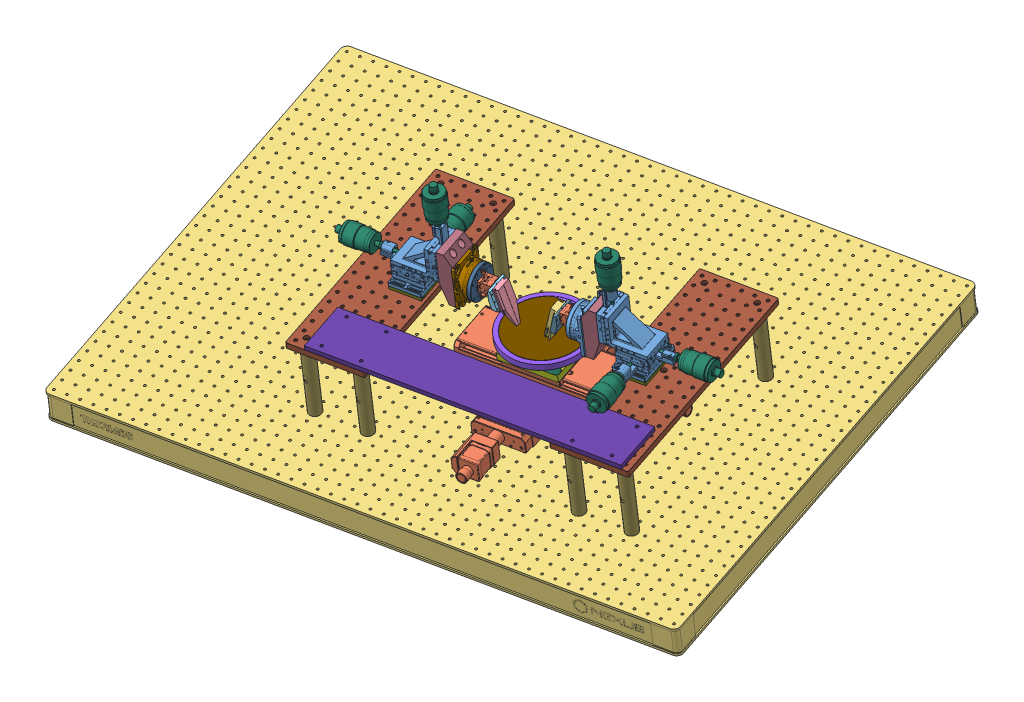
SolidWorks assembly Setup, configuration Default. Lengths in mm.
Overall size (1384.71 521 1150.45).
40 component instances, 21 part files, 108 mates.
Components (placement in the parent):
- 462-XYZ-M-2: 462-XYZ-M [Default] at (49.8158 -112.9792 618.0532) x (0.208851 -0.167911 0.963425) z (-0.977017 0.007153 0.213044) size (111.33 137.01 128.04)
- M-406.62S-4: M-406.62S [Default] at (251.5872 -279.1088 517.8324) x (0.208851 -0.167911 0.963425) z (0.042664 0.985776 0.162558) size (419.5 106.5 40)
- B3648F-Solidworks-1: B3648F-Solidworks [Default] at (-379.5647 -399.4119 1043.9168) x (0.977017 -0.007153 -0.213044) z (0.208851 -0.167911 0.963425) size (1219.2 60 914.4)
- M-406.62S-5: M-406.62S [Default] at (252.9966 -239.634 524.1473) x (0.977017 -0.007153 -0.213044) z (0.042664 0.985776 0.162558) size (419.5 106.5 40)
- HFV002-Solidworks-1: HFV002-Solidworks [Default] at (201.4749 -76.76 602.3122) x (0.208851 -0.167911 0.963425) z (-0.211661 0.954038 0.212159) size (32 13.8 82.5)
- fiber holder adaptor_v2-2: fiber holder adaptor_v2 [Default] at (208.543 -65.9697 592.0326) x (0.977017 -0.007153 -0.213044) z (0.208851 -0.167911 0.963425) size (16.3 42.46 45)
- RP03-Solidworks-1: RP03-Solidworks [Default] at (255.4491 -184.219 533.5338) x (0.977017 -0.007153 -0.213044) z (0.208851 -0.167911 0.963425) size (118.11 17.77 118.11)
- rotation stage adaptor-1: rotation stage adaptor [Default] at (255.3955 -185.4584 533.3295) x (0.977017 -0.007153 -0.213044) z (0.208851 -0.167911 0.963425) size (118.11 15 118.11)
- Wafer chuck-3: Wafer chuck [Default] at (256.7081 -155.1287 538.3309) x (0.208851 -0.167911 0.963425) z (-0.977017 0.007153 0.213044) size (170 13 170)
- PR01 + adaptor-1: PR01 + adaptor [Default] at (135.5181 -100.5643 655.1645) x (0.042664 0.985776 0.162558) z (-0.208851 0.167911 -0.963425) size (88.9 32.89 82.68)
  - PR01-Solidworks-1: PR01-Solidworks [Default] at (32.836 6.2197 50.44) size (88.9 25.27 82.68)
  - PR01A-Solidworks-1: PR01A-Solidworks [Default] at (20.0486 45.6101 48.8975) size (68.58 7.62 68.58)
- MB618-Solidworks-1: MB618-Solidworks [Default] at (11.6774 -131.5526 623.5055) x (-0.208851 0.167911 -0.963425) z (0.977017 -0.007153 -0.213044) size (457.2 12.7 152.4)
- RS6-Solidworks-1: RS6-Solidworks [Default] at (101.1502 -239.3366 794.9313) x (0.999084 -0.042649 -0.003583) z (-0.0034 -0.162562 0.986692) size (25.37 152.4 25.57)
- RS6-Solidworks-2: RS6-Solidworks [Default] at (1.8853 -238.6099 816.5765) x (0.999084 -0.042649 -0.003583) z (-0.0034 -0.162562 0.986692) size (25.37 152.4 25.57)
- RS6-Solidworks-3: RS6-Solidworks [Default] at (-82.9916 -170.3709 425.0407) x (0.999084 -0.042649 -0.003583) z (-0.0034 -0.162562 0.986692) size (25.37 152.4 25.57)
- RS6-Solidworks-4: RS6-Solidworks [Default] at (16.2733 -171.0976 403.3954) x (0.999084 -0.042649 -0.003583) z (-0.0034 -0.162562 0.986692) size (25.37 152.4 25.57)
- XYZ_to_rotation_adapter-1: XYZ_to_rotation_adapter [Default] at (143.7201 -49.9652 576.181) x (0.977017 -0.007153 -0.213044) z (0.208851 -0.167911 0.963425) size (30 110.9 63)
- RS6-Solidworks-5: RS6-Solidworks [Default] at (498.2097 -242.2436 708.3503) x (0.999084 -0.042649 -0.003583) z (-0.0034 -0.162562 0.986692) size (25.37 152.4 25.57)
- RS6-Solidworks-6: RS6-Solidworks [Default] at (597.4746 -242.9703 686.7051) x (0.999084 -0.042649 -0.003583) z (-0.0034 -0.162562 0.986692) size (25.37 152.4 25.57)
- RS6-Solidworks-7: RS6-Solidworks [Default] at (413.3328 -174.0045 316.8145) x (0.999084 -0.042649 -0.003583) z (-0.0034 -0.162562 0.986692) size (25.37 152.4 25.57)
- RS6-Solidworks-8: RS6-Solidworks [Default] at (512.5977 -174.7313 295.1693) x (0.999084 -0.042649 -0.003583) z (-0.0034 -0.162562 0.986692) size (25.37 152.4 25.57)
- MB618-Solidworks-2: MB618-Solidworks [Default] at (508.0018 -135.1863 515.2794) x (0.208851 -0.167911 0.963425) z (-0.977017 0.007153 0.213044) size (457.2 12.7 152.4)
- 462-XYZ-M-3: 462-XYZ-M [Default] at (471.489 -116.2016 526.9252) x (-0.208851 0.167911 -0.963425) z (0.977017 -0.007153 -0.213044) size (111.33 137.01 128.04)
- XYZ_to_rotation_adapter-2: XYZ_to_rotation_adapter [Default] at (382.646 -62.2683 588.0824) x (-0.977017 0.007153 0.213044) z (-0.208851 0.167911 -0.963425) size (30 110.9 63)
- fiber holder adaptor-3: fiber holder adaptor [Default] at (316.9328 -66.8359 568.8384) x (-0.977017 0.007153 0.213044) z (-0.208851 0.167911 -0.963425) size (16.3 42.46 45)
- HR-1-1: HR-1 [Default] at (35.363 -83.6134 535.4344) x (-0.208851 0.167911 -0.963425) z (0.898338 0.422271 -0.121145) size (120.65 42.47 42.47)
- 9021-M-1: 9021-M [-000] at (89.7473 -126.9965 653.5131) x (-0.208851 0.167911 -0.963425) z (0.977017 -0.007153 -0.213044) size (88.9 6.35 63.5)
- 9021-M-2: 9021-M [-000] at (431.0156 -114.7036 489.4007) x (0.208851 -0.167911 0.963425) z (-0.977017 0.007153 0.213044) size (88.9 6.35 63.5)
- HR-1-2: HR-1 [Default] at (490.2951 -116.9267 613.5919) x (0.208851 -0.167911 0.963425) z (-0.977113 0.004869 0.212666) size (120.65 42.47 42.47)
- HR-1-3: HR-1 [Default] at (437.6935 40.0654 562.9779) x (0.042664 0.985776 0.162558) z (-0.014619 -0.162073 0.986671) size (120.65 42.47 42.47)
- HR-1-4: HR-1 [Default] at (558.9388 -87.978 513.9445) x (0.977017 -0.007153 -0.213044) z (0.213048 -0.000193 0.977042) size (120.65 42.47 42.47)
- HR-1-5: HR-1 [Default] at (111.6919 42.524 633.6286) x (0.042664 0.985776 0.162558) z (-0.014619 -0.162073 0.986671) size (120.65 42.47 42.47)
- HR-1-6: HR-1 [Default] at (-33.4526 -81.215 648.1957) x (-0.977017 0.007153 0.213044) z (-0.149484 -0.73549 -0.660839) size (120.65 42.47 42.47)
- Steel board for electrical probing-1: Steel board for electrical probing [Default] at (309.9232 -150.7955 740.0482) x (0.977017 -0.007153 -0.213044) z (0.208851 -0.167911 0.963425) size (609.6 9.53 101.6)
- Si_wafer-1: Si_wafer [Default] at (256.6868 -155.6216 538.2497) x (-0.977017 0.007153 0.213044) z (-0.208851 0.167911 -0.963425) size (150 0.68 144.27)
- PR01 + adaptor-2: PR01 + adaptor [Default] at (387.6576 -85.3854 496.9428) x (0.042664 0.985776 0.162558) z (0.208851 -0.167911 0.963425) size (88.9 32.89 82.68)
- GN2- no base-1: GN2- no base [Default] at (347.9491 -72.0384 563.6041) x (0.208851 -0.167911 0.963425) z (-0.042664 -0.985776 -0.162558) size (41.69 25.4 41.69)
- GN2- no base-2: GN2- no base [Default] at (177.1294 -69.947 595.753) x (-0.208851 0.167911 -0.963425) z (-0.042664 -0.985776 -0.162558) size (41.69 25.4 41.69)
- HFA001-Solidworks-1: HFA001-Solidworks [Default] at (294.6948 -119.3232 572.7949) x (0.208851 -0.167911 0.963425) z (-0.29408 -0.950335 -0.101879) size (32 18.4 82.5)
Mates (geometry in assembly coordinates):
- Concentric2: concentric aligned: circle of 462-XYZ-M-2; circle of ?
- Parallel3: parallel anti-aligned: plane of ? through (-0.0295 415.3071 736.2171) normal (1 0 0); plane of ? through (-0.0295 415.3071 736.2171) normal (-1 0 0)
- Concentric16: concentric anti-aligned: circle of ?; circle of ?
- Coincident18: coincident anti-aligned: plane of ? through (-0.0295 415.3071 736.2171) normal (1 0 0); plane of ? through (-0.0295 415.3071 736.2171) normal (-1 0 0)
- Concentric18: concentric aligned: circle of ?; circle of 462-XYZ-M-2
- Coincident28: coincident anti-aligned: plane of M-406.62S-4 through (170.6352 -255.4722 395.7427) normal (-0.042664 -0.985776 -0.162558); plane of B3648F-Solidworks-1 through (803.9028 -347.5029 787.6282) normal (0.042664 0.985776 0.162558)
- Concentric25: concentric anti-aligned: circle of M-406.62S-4; circle of M-406.62S-5
- Concentric26: concentric anti-aligned: circle of M-406.62S-4; circle of M-406.62S-5
- Coincident34: coincident anti-aligned: plane of M-406.62S-4 through (203.4248 -229.7457 477.1934) normal (0.042664 0.985776 0.162558); plane of M-406.62S-5 through (128.8011 -247.5846 604.9562) normal (-0.042664 -0.985776 -0.162558)
- Concentric27: concentric: circle of ?; circle of M-406.62S-5
- Concentric28: concentric: circle of ?; circle of M-406.62S-5
- Coincident45: coincident aligned: line of ? through (88.2913 599.9288 735.0554) axis (0.258819 -0.965926 0); line of HFV002-Solidworks-1 through (92.5967 583.8609 735.0554) axis (0.258819 -0.965926 0)
- Coincident48: coincident: circle of M-406.62S-5; circle of ?
- Coincident49: coincident anti-aligned: plane of 462-XYZ-M-2; plane of ? through (-25.4295 447.3565 724.0251) normal (-1 0 0)
- Concentric32: concentric anti-aligned: circle of M-406.62S-5; circle of rotation stage adaptor-1
- Concentric33: concentric anti-aligned: circle of RP03-Solidworks-1; circle of rotation stage adaptor-1
- Coincident52: coincident anti-aligned: line of RP03-Solidworks-1 through (235.2245 197.9665 813.201) axis (-1 0 0); line of rotation stage adaptor-1 through (125.3695 197.9665 813.201) axis (1 0 0)
- Coincident53: coincident aligned: plane of M-406.62S-5; circle of rotation stage adaptor-1
- Parallel6: parallel aligned: plane of M-406.62S-5 through (128.8011 -247.5846 604.9562) normal (0.208851 -0.167911 0.963425); plane of rotation stage adaptor-1 through (209.3915 -209.7386 600.3674) normal (0.208851 -0.167911 0.963425)
- Coincident55: coincident anti-aligned: plane of RP03-Solidworks-1 through (256.1535 -167.9438 536.2177) normal (0.042664 0.985776 0.162558); plane of Wafer chuck-3 through (256.1535 -167.9438 536.2177) normal (-0.042664 -0.985776 -0.162558)
- Coincident57: coincident anti-aligned: plane of HFV002-Solidworks-1 through (204.2999 -63.944 580.8623) normal (-0.954768 -0.248228 0.163711); plane of fiber holder adaptor_v2-2 through (207.6467 -66.6348 596.3012) normal (0.954768 0.248228 -0.163711)
- Parallel7: parallel anti-aligned: plane of M-406.62S-5 through (120.3558 -214.4056 612.0506) normal (-0.977017 0.007153 0.213044); plane of MB618-Solidworks-1 through (138.3371 -158.164 829.7652) normal (0.977017 -0.007153 -0.213044)
- Concentric42: concentric aligned: circle of MB618-Solidworks-1; circle of RS6-Solidworks-1
- Coincident68: coincident anti-aligned: plane of MB618-Solidworks-1 through (134.8643 -170.6619 828.3399) normal (-0.042664 -0.985776 -0.162558); plane of RS6-Solidworks-1 through (108.3008 -166.7405 811.5313) normal (0.042664 0.985776 0.162558)
- Concentric43: concentric anti-aligned: circle of MB618-Solidworks-1; circle of RS6-Solidworks-2
- Coincident69: coincident anti-aligned: plane of MB618-Solidworks-1 through (134.8643 -170.6619 828.3399) normal (-0.042664 -0.985776 -0.162558); plane of RS6-Solidworks-2 through (9.036 -166.0137 833.1766) normal (0.042664 0.985776 0.162558)
- Concentric44: concentric aligned: circle of MB618-Solidworks-1; circle of RS6-Solidworks-3
- Coincident70: coincident anti-aligned: plane of MB618-Solidworks-1 through (134.8643 -170.6619 828.3399) normal (-0.042664 -0.985776 -0.162558); plane of RS6-Solidworks-3 through (-75.8409 -97.7747 441.6407) normal (0.042664 0.985776 0.162558)
- Concentric45: concentric aligned: circle of MB618-Solidworks-1; circle of RS6-Solidworks-4
- Coincident71: coincident anti-aligned: plane of MB618-Solidworks-1 through (134.8643 -170.6619 828.3399) normal (-0.042664 -0.985776 -0.162558); plane of RS6-Solidworks-4 through (23.424 -98.5014 419.9955) normal (0.042664 0.985776 0.162558)
- Concentric46: concentric aligned: circle of B3648F-Solidworks-1; circle of RS6-Solidworks-4
- Coincident72: coincident anti-aligned: plane of B3648F-Solidworks-1 through (803.9028 -347.5029 787.6282) normal (0.042664 0.985776 0.162558); plane of RS6-Solidworks-4 through (16.922 -248.7337 395.2217) normal (-0.042664 -0.985776 -0.162558)
- Coincident74: coincident anti-aligned: plane of HFV002-Solidworks-1 through (207.3335 -66.3829 594.8561) normal (-0.208851 0.167911 -0.963425); plane of fiber holder adaptor_v2-2 through (214.9507 -107.9998 585.9516) normal (0.208851 -0.167911 0.963425)
- Concentric51: concentric aligned: cylinder of 462-XYZ-M-2 through (87.1315 -118.2269 653.2078) axis (0.042664 0.985776 0.162558) radius 5.1562; circle of MB618-Solidworks-1
- Concentric55: concentric anti-aligned: circle of 462-XYZ-M-2; circle of MB618-Solidworks-1
- Coincident80: coincident anti-aligned: plane of M-406.62S-5 through (206.6178 -206.2983 580.233) normal (0.042664 0.985776 0.162558); plane of rotation stage adaptor-1 through (254.7555 -200.245 530.8911) normal (-0.042664 -0.985776 -0.162558)
- Coincident81: coincident anti-aligned: plane of RP03-Solidworks-1 through (310.044 -190.0736 546.9742) normal (-0.042664 -0.985776 -0.162558); plane of rotation stage adaptor-1 through (255.3955 -185.4584 533.3295) normal (0.042664 0.985776 0.162558)
- Concentric56: concentric aligned: circle of 462-XYZ-M-2; circle of XYZ_to_rotation_adapter-1
- Concentric57: concentric aligned: circle of 462-XYZ-M-2; circle of XYZ_to_rotation_adapter-1
- Coincident82: coincident anti-aligned: plane of 462-XYZ-M-2 through (112.2708 -8.1117 594.4874) normal (0.977017 -0.007153 -0.213044); plane of XYZ_to_rotation_adapter-1 through (125.5344 -16.2211 655.5863) normal (-0.977017 0.007153 0.213044)
- Concentric58: concentric aligned: circle of PR01 + adaptor-1/PR01-Solidworks-1; circle of XYZ_to_rotation_adapter-1
- Concentric59: concentric anti-aligned: circle of PR01 + adaptor-1/PR01-Solidworks-1; circle of XYZ_to_rotation_adapter-1
- Coincident83: coincident anti-aligned: plane of PR01 + adaptor-1/PR01-Solidworks-1 through (137.0391 -112.008 570.7469) normal (-0.977017 0.007153 0.213044); plane of XYZ_to_rotation_adapter-1 through (150.1135 -125.7582 631.1673) normal (0.977017 -0.007153 -0.213044)
- Concentric60: concentric anti-aligned: circle of RS6-Solidworks-5; circle of B3648F-Solidworks-1
- Coincident85: coincident anti-aligned: plane of B3648F-Solidworks-1 through (803.9028 -347.5029 787.6282) normal (0.042664 0.985776 0.162558); plane of RS6-Solidworks-5 through (498.8584 -319.8797 700.1766) normal (-0.042664 -0.985776 -0.162558)
- Concentric61: concentric anti-aligned: circle of B3648F-Solidworks-1; circle of RS6-Solidworks-3
- Concentric63: concentric aligned: circle of RS6-Solidworks-6; circle of B3648F-Solidworks-1
- Coincident88: coincident anti-aligned: plane of B3648F-Solidworks-1 through (803.9028 -347.5029 787.6282) normal (0.042664 0.985776 0.162558); plane of RS6-Solidworks-6 through (598.1233 -320.6064 678.5313) normal (-0.042664 -0.985776 -0.162558)
- Concentric64: concentric aligned: circle of RS6-Solidworks-7; circle of B3648F-Solidworks-1
- Coincident89: coincident anti-aligned: plane of B3648F-Solidworks-1 through (803.9028 -347.5029 787.6282) normal (0.042664 0.985776 0.162558); plane of RS6-Solidworks-7 through (413.9815 -251.6407 308.6407) normal (-0.042664 -0.985776 -0.162558)
- Concentric65: concentric aligned: circle of RS6-Solidworks-8; circle of B3648F-Solidworks-1
- Coincident90: coincident anti-aligned: plane of B3648F-Solidworks-1 through (803.9028 -347.5029 787.6282) normal (0.042664 0.985776 0.162558); circle of RS6-Solidworks-8
- Concentric66: concentric aligned: circle of RS6-Solidworks-6; circle of MB618-Solidworks-2
- Concentric69: concentric aligned: circle of RS6-Solidworks-7; circle of MB618-Solidworks-2
- Coincident92: coincident anti-aligned: plane of RS6-Solidworks-6 through (604.6252 -170.3742 703.3052) normal (0.042664 0.985776 0.162558); plane of MB618-Solidworks-2 through (393.92 -97.4869 316.606) normal (-0.042664 -0.985776 -0.162558)
- Parallel9: parallel aligned: plane of RP03-Solidworks-1 through (326.1583 -178.8957 580.4303) normal (0.208851 -0.167911 0.963425); plane of rotation stage adaptor-1 through (209.3915 -209.7386 600.3674) normal (0.208851 -0.167911 0.963425)
- Parallel11: parallel aligned: plane of rotation stage adaptor-1 through (209.3915 -209.7386 600.3674) normal (0.208851 -0.167911 0.963425); plane of Wafer chuck-3 through (255.0624 -164.555 589.7734) normal (0.208851 -0.167911 0.963425)
- Concentric70: concentric anti-aligned: circle of RP03-Solidworks-1; circle of Wafer chuck-3
- Concentric71: concentric anti-aligned: circle of MB618-Solidworks-2; circle of 462-XYZ-M-3
- Concentric72: concentric aligned: circle of MB618-Solidworks-2; circle of 462-XYZ-M-3
- Concentric73: concentric anti-aligned: circle of 462-XYZ-M-3; circle of XYZ_to_rotation_adapter-2
- Concentric74: concentric anti-aligned: circle of 462-XYZ-M-3; circle of XYZ_to_rotation_adapter-2
- Coincident97: coincident anti-aligned: plane of 462-XYZ-M-3 through (426.8602 -20.9675 589.8819) normal (-0.977017 0.007153 0.213044); plane of XYZ_to_rotation_adapter-2 through (413.8103 -7.9214 529.5971) normal (0.977017 -0.007153 -0.213044)
- Concentric90: concentric anti-aligned: circle of 462-XYZ-M-2; cylinder of HR-1-1 through (55.3838 -92.5276 624.6035) axis (0.208851 -0.167911 0.963425) radius 2.9845
- Coincident110: coincident anti-aligned: line of HFV002-Solidworks-1 through (204.2999 -63.944 580.8623) axis (0.208851 -0.167911 0.963425); line of fiber holder adaptor_v2-2 through (207.0202 -66.1311 593.4109) axis (-0.208851 0.167911 -0.963425)
- Coincident114: coincident anti-aligned: plane of 462-XYZ-M-2 through (51.2953 -86.3851 557.9578) normal (-0.208851 0.167911 -0.963425); plane of HR-1-1 through (74.358 -156.9773 540.6551) normal (0.208851 -0.167911 0.963425)
- Coincident115: coincident anti-aligned: plane of MB618-Solidworks-1 through (135.4061 -158.1425 830.4044) normal (0.042664 0.985776 0.162558); plane of 9021-M-1 through (94.2998 -127.7015 656.5936) normal (-0.042664 -0.985776 -0.162558)
- Concentric92: concentric anti-aligned: circle of MB618-Solidworks-1; circle of 9021-M-1
- Concentric93: concentric anti-aligned: circle of MB618-Solidworks-1; circle of 9021-M-1
- Coincident116: coincident anti-aligned: plane of 462-XYZ-M-2 through (32.9944 -121.0544 671.4373) normal (-0.042664 -0.985776 -0.162558); plane of 9021-M-1 through (94.5707 -121.4418 657.6259) normal (0.042664 0.985776 0.162558)
- Concentric94: concentric anti-aligned: circle of MB618-Solidworks-2; circle of 9021-M-2
- Concentric95: concentric aligned: circle of MB618-Solidworks-2; circle of 9021-M-2
- Coincident118: coincident anti-aligned: plane of 462-XYZ-M-3 through (497.4154 -109.5364 479.702) normal (-0.042664 -0.985776 -0.162558); plane of 9021-M-2 through (435.8391 -109.149 493.5135) normal (0.042664 0.985776 0.162558)
- Coincident119: coincident anti-aligned: plane of MB618-Solidworks-2 through (394.4619 -84.9676 318.6705) normal (0.042664 0.985776 0.162558); plane of 9021-M-2 through (435.5682 -115.4086 492.4812) normal (-0.042664 -0.985776 -0.162558)
- Concentric96: concentric anti-aligned: circle of 462-XYZ-M-3; circle of HR-1-2
- Coincident120: coincident anti-aligned: plane of 462-XYZ-M-3 through (480.5232 -111.6554 598.5492) normal (0.208851 -0.167911 0.963425); plane of HR-1-2 through (487.2347 -190.4506 583.3614) normal (-0.208851 0.167911 -0.963425)
- Concentric97: concentric anti-aligned: circle of 462-XYZ-M-3; circle of HR-1-3
- Coincident121: coincident anti-aligned: plane of 462-XYZ-M-3 through (427.0898 20.2756 553.7828) normal (0.042664 0.985776 0.162558); plane of HR-1-3 through (518.7749 14.7625 563.1518) normal (-0.042664 -0.985776 -0.162558)
- Concentric98: concentric anti-aligned: circle of 462-XYZ-M-3; circle of HR-1-4
- Coincident122: coincident anti-aligned: plane of 462-XYZ-M-3 through (544.4908 -87.8312 530.5695) normal (0.977017 -0.007153 -0.213044); plane of HR-1-4 through (541.984 -166.0507 521.6995) normal (-0.977017 0.007153 0.213044)
- Concentric99: concentric anti-aligned: circle of 462-XYZ-M-2; circle of HR-1-5
- Coincident123: coincident anti-aligned: plane of 462-XYZ-M-2 through (115.0104 19.2513 641.8999) normal (0.042664 0.985776 0.162558); plane of HR-1-5 through (192.7733 17.2211 633.8025) normal (-0.042664 -0.985776 -0.162558)
- Concentric100: concentric anti-aligned: circle of 462-XYZ-M-2; circle of HR-1-6
- Coincident124: coincident anti-aligned: plane of 462-XYZ-M-2 through (-11.3784 -80.313 630.8675) normal (-0.977017 0.007153 0.213044); plane of HR-1-6 through (3.843 -134.5952 702.4952) normal (0.977017 -0.007153 -0.213044)
- Coincident125: coincident anti-aligned: plane of MB618-Solidworks-1 through (135.4061 -158.1425 830.4044) normal (0.042664 0.985776 0.162558); plane of Steel board for electrical probing-1 through (314.4757 -151.5005 743.1287) normal (-0.042664 -0.985776 -0.162558)
- Parallel12: parallel aligned: plane of MB618-Solidworks-2 through (489.3218 -161.2328 756.258) normal (0.208851 -0.167911 0.963425); plane of Steel board for electrical probing-1 through (27.6971 -148.4606 858.5547) normal (0.208851 -0.167911 0.963425)
- Concentric101: concentric aligned: circle of MB618-Solidworks-2; circle of Steel board for electrical probing-1
- Concentric106: concentric aligned: circle of Wafer chuck-3; circle of Si_wafer-1
- Parallel13: parallel aligned: plane of rotation stage adaptor-1 through (184.7241 -189.9066 486.5773) normal (-0.208851 0.167911 -0.963425); plane of Si_wafer-1 through (270.3088 -144.1959 465.3875) normal (-0.208851 0.167911 -0.963425)
- Coincident128: coincident anti-aligned: plane of Wafer chuck-3 through (256.6868 -155.6216 538.2497) normal (0.042664 0.985776 0.162558); plane of Si_wafer-1 through (256.6868 -155.6216 538.2497) normal (-0.042664 -0.985776 -0.162558)
- Concentric110: concentric aligned: cylinder of XYZ_to_rotation_adapter-2 through (392.0313 -117.8199 574.2247) axis (-0.977017 0.007153 0.213044) radius 2.5527; cylinder of PR01 + adaptor-2 through (392.0313 -117.8199 574.2247) axis (-0.977017 0.007153 0.213044) radius 3.429
- Concentric111: concentric aligned: cylinder of XYZ_to_rotation_adapter-2 through (384.4559 -39.1817 536.8438) axis (-0.977017 0.007153 0.213044) radius 2.5527; cylinder of PR01 + adaptor-2 through (384.4559 -39.1817 536.8438) axis (-0.977017 0.007153 0.213044) radius 3.429
- Coincident129: coincident anti-aligned: plane of XYZ_to_rotation_adapter-2 through (379.7684 -117.0294 517.9607) normal (-0.977017 0.007153 0.213044); plane of PR01 + adaptor-2 through (393.1137 -124.5199 579.4134) normal (0.977017 -0.007153 -0.213044)
- Concentric117: concentric aligned: circle of PR01 + adaptor-2; circle of GN2- no base-1
- Concentric118: concentric aligned: circle of PR01 + adaptor-2; circle of GN2- no base-1
- Coincident132: coincident anti-aligned: plane of PR01 + adaptor-2 through (356.1071 -78.2659 562.5444) normal (-0.977017 0.007153 0.213044); plane of GN2- no base-1 through (352.9129 -88.6528 548.2444) normal (0.977017 -0.007153 -0.213044)
- Concentric119: concentric anti-aligned: cylinder of fiber holder adaptor-3 through (319.935 -70.2609 562.5534) axis (0.977017 -0.007153 -0.213044) radius 1.632; cylinder of GN2- no base-1 through (329.7051 -70.3324 560.423) axis (-0.977017 0.007153 0.213044) radius 1.4224
- Concentric120: concentric anti-aligned: cylinder of fiber holder adaptor-3 through (323.6483 -73.2464 579.6831) axis (0.977017 -0.007153 -0.213044) radius 1.632; cylinder of GN2- no base-1 through (333.4185 -73.3179 577.5527) axis (-0.977017 0.007153 0.213044) radius 1.4224
- Coincident133: coincident anti-aligned: plane of fiber holder adaptor-3 through (325.3383 -103.2691 541.5025) normal (0.977017 -0.007153 -0.213044); plane of GN2- no base-1 through (333.9433 -80.2167 580.1912) normal (-0.977017 0.007153 0.213044)
- Concentric122: concentric aligned: cylinder of PR01 + adaptor-1/PR01A-Solidworks-1 through (175.8158 -64.7251 592.5931) axis (0.977017 -0.007153 -0.213044) radius 1.0922; cylinder of GN2- no base-2 through (175.8158 -64.7251 592.5931) axis (0.977017 -0.007153 -0.213044) radius 1.1811
- Concentric123: concentric aligned: cylinder of PR01 + adaptor-1/PR01A-Solidworks-1 through (180.2188 -68.265 612.9041) axis (0.977017 -0.007153 -0.213044) radius 1.0922; circle of GN2- no base-2
- Coincident134: coincident anti-aligned: plane of PR01 + adaptor-1/PR01A-Solidworks-1 through (177.5676 -76.8861 601.0351) normal (0.977017 -0.007153 -0.213044); plane of GN2- no base-2 through (179.6781 -91.538 611.2061) normal (-0.977017 0.007153 0.213044)
- Concentric127: concentric anti-aligned: cylinder of fiber holder adaptor_v2-2 through (210.5681 -69.3875 585.9606) axis (-0.977017 0.007153 0.213044) radius 1.632; circle of GN2- no base-2
- Concentric128: concentric anti-aligned: cylinder of fiber holder adaptor_v2-2 through (214.2815 -72.373 603.0903) axis (-0.977017 0.007153 0.213044) radius 1.632; cylinder of GN2- no base-2 through (204.5113 -72.3014 605.2208) axis (0.977017 -0.007153 -0.213044) radius 1.4224
- Coincident135: coincident anti-aligned: plane of fiber holder adaptor_v2-2 through (205.8294 -109.8086 612.5248) normal (-0.977017 0.007153 0.213044); plane of GN2- no base-2 through (199.7314 -74.9353 583.3883) normal (0.977017 -0.007153 -0.213044)
- Coincident136: coincident: plane of fiber holder adaptor-3 through (310.8547 -108.1029 561.4068) normal (0.208851 -0.167911 0.963425); plane of HFA001-Solidworks-1 through (322.0683 -66.6239 566.2051) normal (-0.208851 0.167911 -0.963425)
- Coincident137: coincident: plane of fiber holder adaptor-3 through (322.3816 -66.8758 567.6503) normal (-0.932683 0.262047 0.247857); plane of HFA001-Solidworks-1 through (318.8514 -64.0376 551.3654) normal (0.932683 -0.262047 -0.247857)
- Coincident138: coincident aligned: line of fiber holder adaptor-3 through (323.0081 -67.3795 570.5405) axis (0.208851 -0.167911 0.963425); line of HFA001-Solidworks-1 through (322.6844 -67.1193 569.0472) axis (0.208851 -0.167911 0.963425)
